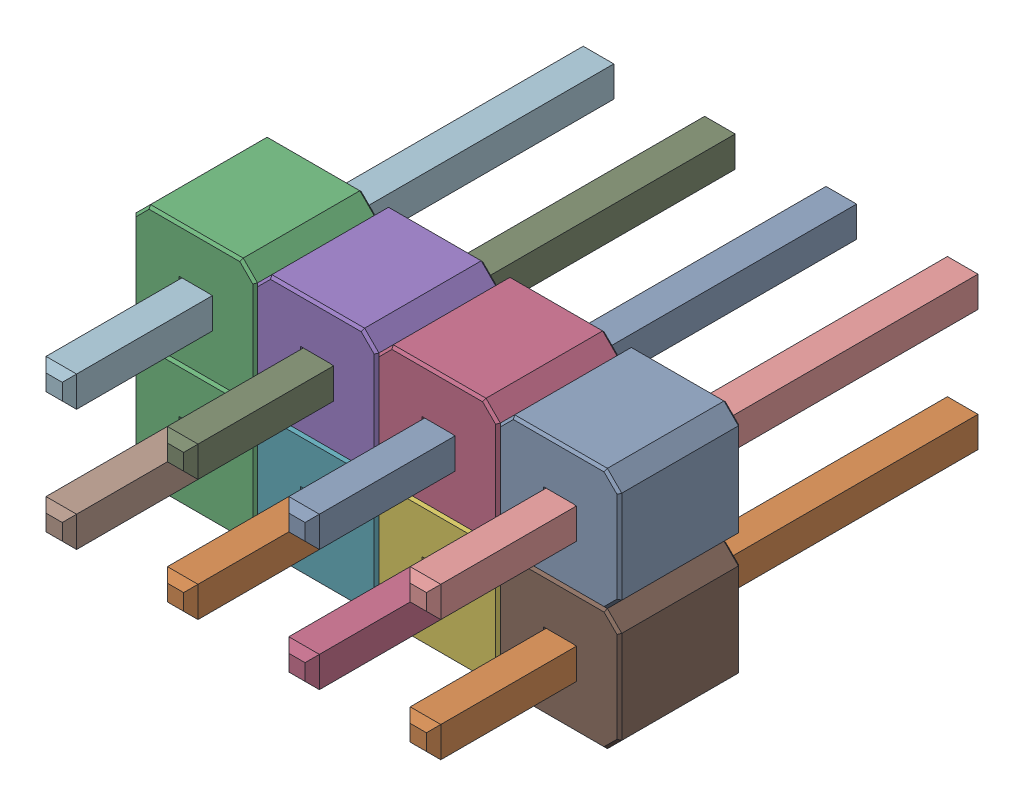
SolidWorks assembly X1_XLR2, configuration Default. Lengths in mm.
Overall size (10.16 5.08 11.54).
17 component instances, 2 part files, 0 mates.
Components (placement in the parent):
- PLD-8-1: PLD-8 [Default] at (111.6251 88.0429 -1.2114) x (1 0 0) z (0 0 -1) size (10.16 5.08 11.54)
  - _______________________-1: _______________________ [Default] at (-2.54 0 -3) size (0.64 0.64 11.54)
  - _______________________-2: _______________________ [Default] at (-5.08 2.54 -3) size (0.64 0.64 11.54)
  - _________-1: _________ [Default] at (-7.6724 2.5342 -0.0112) size (2.54 2.54 2.54)
  - _______________________-3: _______________________ [Default] at (-2.54 2.54 -3) size (0.64 0.64 11.54)
  - _________-2: _________ [Default] at (-5.1324 -0.0058 -0.0112) size (2.54 2.54 2.54)
  - _________-3: _________ [Default] at (-2.5924 2.5342 -0.0112) size (2.54 2.54 2.54)
  - _________-4: _________ [Default] at (-5.1324 2.5342 -0.0112) size (2.54 2.54 2.54)
  - _______________________-4: _______________________ [Default] at (-7.62 2.54 -3) size (0.64 0.64 11.54)
  - _______________________-5: _______________________ [Default] at (-5.08 0 -3) size (0.64 0.64 11.54)
  - _______________________-6: _______________________ [Default] at (0 0 -3) size (0.64 0.64 11.54)
  - _________-5: _________ [Default] at (-0.0524 2.5342 -0.0112) size (2.54 2.54 2.54)
  - _______________________-7: _______________________ [Default] at (-7.62 0 -3) size (0.64 0.64 11.54)
  - _________-6: _________ [Default] at (-0.0524 -0.0058 -0.0112) size (2.54 2.54 2.54)
  - _______________________-8: _______________________ [Default] at (0 2.54 -3) size (0.64 0.64 11.54)
  - _________-7: _________ [Default] at (-7.6724 -0.0058 -0.0112) size (2.54 2.54 2.54)
  - _________-8: _________ [Default] at (-2.5924 -0.0058 -0.0112) size (2.54 2.54 2.54)
